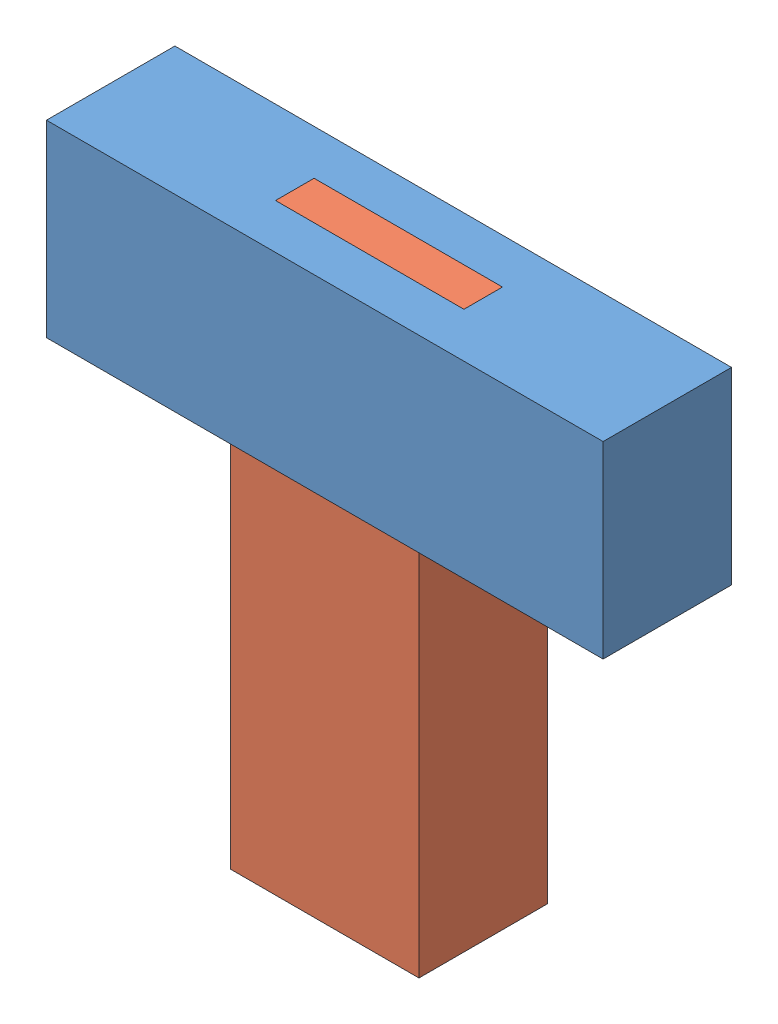
SolidWorks assembly Assem2, configuration Default. Lengths in mm.
Overall size (130 130 30).
2 component instances, 2 part files, 2 mates.
Components (placement in the parent):
- Mortice-1: Mortice [Default] at (-15.4758 10.0394 1.3457) size (130 44 30)
- Tenon-1: Tenon [Default] at (-15.4758 -32.9606 1.3457) size (44 130 30)
Mates (geometry in assembly coordinates):
- Coincident1: coincident anti-aligned: plane of Mortice-1 through (6.5242 -11.9606 5.8457) normal (0 0 -1); plane of Tenon-1 through (-37.4758 32.0394 5.8457) normal (0 0 1)
- Coincident2: coincident aligned: line of Mortice-1 through (-37.4758 32.0394 -3.1543) axis (0 0 1); line of Tenon-1 through (-37.4758 32.0394 -3.1543) axis (0 0 1)
